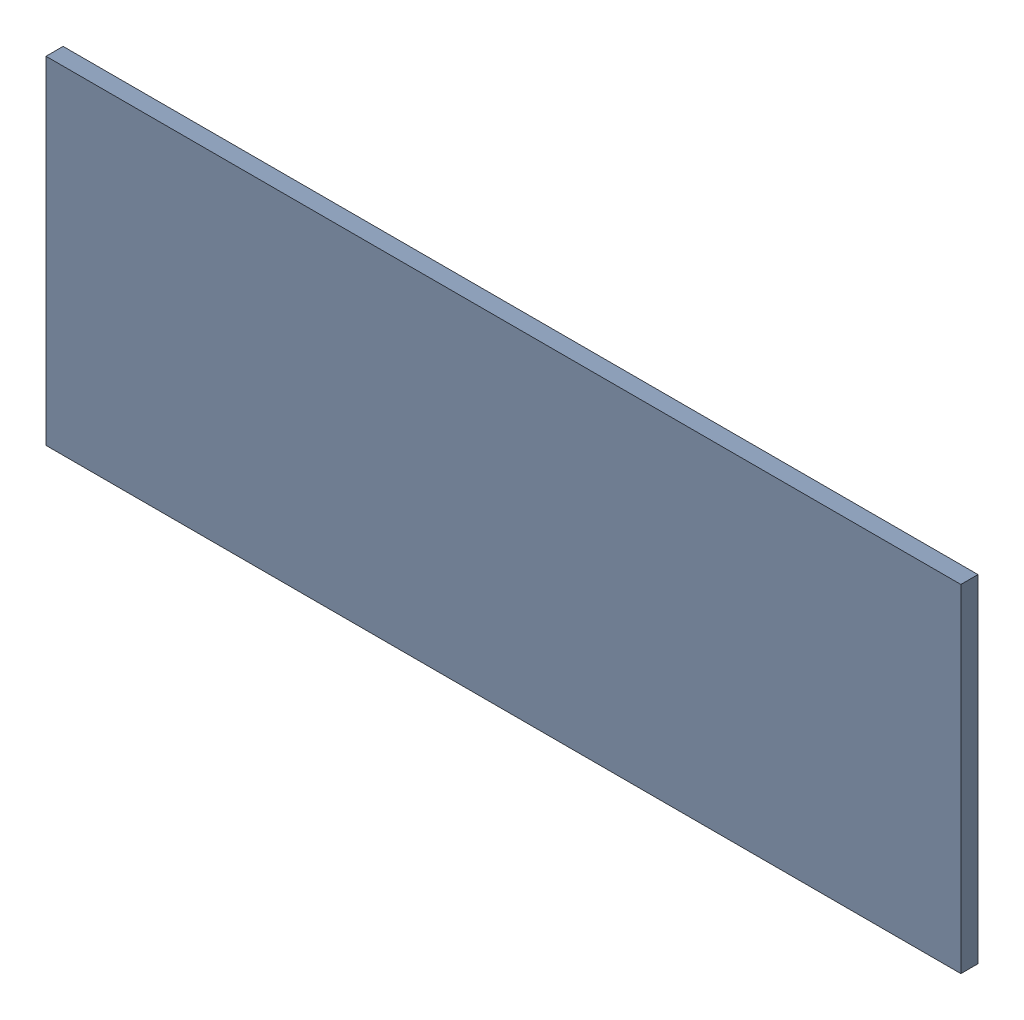
SolidWorks assembly Pad RAK4600-13(14.5mm,12.5mm) on Top Layer, configuration Predeterminado. Lengths in mm.
Overall size (1.9 0.7 0.04).
2 component instances, 1 part files, 0 mates.
Components (placement in the parent):
- Pad RAK4600-13(14.5mm,12.5mm) on Top Layer-1-1: Pad RAK4600-13(14.5mm,12.5mm) on Top Layer-1 [Predeterminado] at (-68.317 -44.187 -0.0457) size (1.9 0.7 0.04)
  - Pad RAK4600-13(14.5mm,12.5mm) on Top Layer-Part-1-1: Pad RAK4600-13(14.5mm,12.5mm) on Top Layer-Part-1 [Predeterminado] at origin size (1.9 0.7 0.04)
